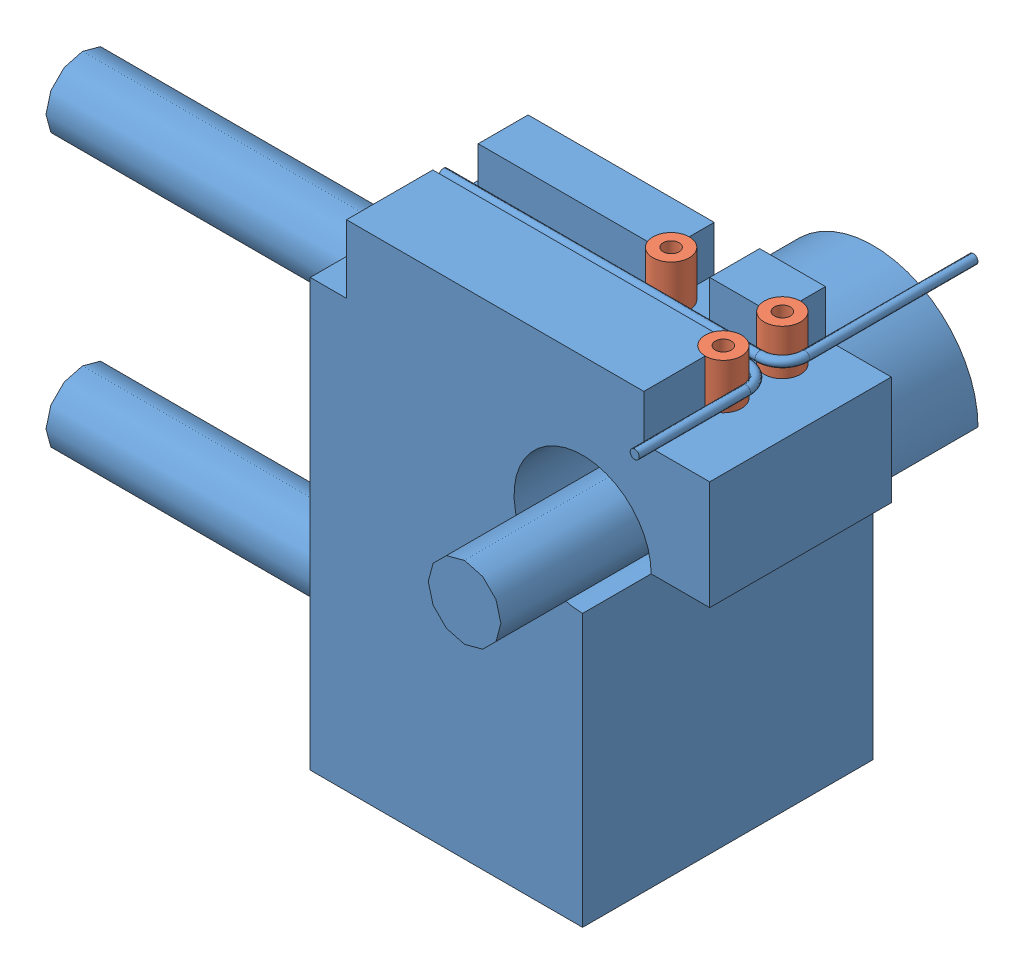
SolidWorks assembly Gantry Holder, vert, assy, configuration Default. Lengths in mm.
Overall size (44 54.5 37.3).
8 component instances, 3 part files, 24 mates.
Components (placement in the parent):
- Gantry Holder, Vert Rod-1: Gantry Holder, Vert Rod [Default] at origin size (81.1 54.5 50)
- 12 x 4 x 4 bearing-1: 12 x 4 x 4 bearing [Default] at (6.75 18 -3.25) size (12 4 12) (hidden)
- 12 x 4 x 4 bearing-2: 12 x 4 x 4 bearing [Default] at (6.75 22 -3.25) size (12 4 12) (hidden)
- 12 x 4 x 4 bearing-3: 12 x 4 x 4 bearing [Default] at (6.75 22 3.25) x (0.997259 0 -0.073987) z (0.073987 0 0.997259) size (12 4 12) (hidden)
- 12 x 4 x 4 bearing-4: 12 x 4 x 4 bearing [Default] at (6.75 18 3.25) x (0.584981 0 -0.811047) z (0.811047 0 0.584981) size (12 4 12) (hidden)
- 4mm dowel-1: 4mm dowel [Default] at (6.75 5 3.25) x (0.933427 0 -0.358767) z (0.358767 0 0.933427) size (4 12 4)
- 4mm dowel-2: 4mm dowel [Default] at (6.75 5 -3.25) x (0.21535 0 0.976537) z (-0.976537 0 0.21535) size (4 12 4)
- 4mm dowel-3: 4mm dowel [Default] at (-5.5 5 -3.25) x (0.21535 0 0.976537) z (-0.976537 0 0.21535) size (4 12 4)
Mates (geometry in assembly coordinates):
- Coincident1: coincident anti-aligned: plane of 12 x 4 x 4 bearing-1 through (12.25 22 -3.25) normal (0 1 0); plane of 12 x 4 x 4 bearing-2 through (9.25 22 -3.25) normal (0 -1 0)
- Concentric1: concentric aligned: cylinder of 12 x 4 x 4 bearing-1 through (6.75 18 -3.25) axis (0 -1 0) radius 6; cylinder of 12 x 4 x 4 bearing-2 through (6.75 22 -3.25) axis (0 -1 0) radius 6
- Coincident2: coincident anti-aligned: plane of 12 x 4 x 4 bearing-3 through (9.2431 22 3.065) normal (0 -1 0); plane of 12 x 4 x 4 bearing-4 through (9.9674 22 -1.2108) normal (0 1 0)
- Concentric2: concentric aligned: cylinder of 12 x 4 x 4 bearing-3 through (6.75 22 3.25) axis (0 -1 0) radius 6; cylinder of 12 x 4 x 4 bearing-4 through (6.75 18 3.25) axis (0 -1 0) radius 6
- Concentric3: concentric: cylinder of assembly; point of Gantry Holder, Vert Rod-1; cylinder of 12 x 4 x 4 bearing-4 through (6.75 18 3.25) axis (0 -1 0) radius 2
- Distance1: distance = 1 mm anti-aligned: plane of Gantry Holder, Vert Rod-1 through (0 17 12) normal (0 1 0); plane of 12 x 4 x 4 bearing-4 through (8.2125 18 1.2224) normal (0 -1 0)
- Coincident5: coincident aligned: plane of 12 x 4 x 4 bearing-1 through (9.25 18 -3.25) normal (0 -1 0); plane of 12 x 4 x 4 bearing-4 through (8.2125 18 1.2224) normal (0 -1 0)
- Concentric4: concentric: cylinder of assembly; point of Gantry Holder, Vert Rod-1; cylinder of 12 x 4 x 4 bearing-1 through (6.75 18 -3.25) axis (0 -1 0) radius 2
- Concentric5: concentric: cylinder of 12 x 4 x 4 bearing-4 through (6.75 18 3.25) axis (0 -1 0) radius 2
- Coincident8: coincident: plane of 12 x 4 x 4 bearing-4 through (9.9674 22 -1.2108) normal (0 1 0)
- Parallel1: parallel aligned: plane of Gantry Holder, Vert Rod-1 through (0 0 12) normal (0 0 1); plane of string-1 through (9 17 53) normal (0 0 1)
- Concentric6: concentric: cylinder of 12 x 4 x 4 bearing-1 through (6.75 18 -3.25) axis (0 -1 0) radius 2
- Coincident11: coincident: plane of 12 x 4 x 4 bearing-1 through (12.25 22 -3.25) normal (0 1 0)
- Parallel2: parallel: plane of Gantry Holder, Vert Rod-1 through (0 17 12) normal (0 1 0); line of string-2 through (9 17 -53) axis (0 0 1)
- Parallel3: parallel: plane of Gantry Holder, Vert Rod-1 through (0 17 12) normal (0 1 0); line of string-2 through (3 17 3) axis (-1 0 0)
- Parallel4: parallel: plane of Gantry Holder, Vert Rod-1 through (0 0 12) normal (0 0 1); line of string-2 through (3 17 3) axis (-1 0 0)
- Parallel5: parallel: plane of Gantry Holder, Vert Rod-1 through (0 17 12) normal (0 1 0); line of string-1 through (-47 17 -3) axis (1 0 0)
- Coincident12: coordinate: unknown of Gantry Holder, Vert Rod-1
- Concentric7: concentric anti-aligned: cylinder of Gantry Holder, Vert Rod-1 through (6.75 17 3.25) axis (0 1 0) radius 2; cylinder of 4mm dowel-1 through (6.75 17 3.25) axis (0 -1 0) radius 2
- Concentric8: concentric anti-aligned: cylinder of Gantry Holder, Vert Rod-1 through (6.75 17 -3.25) axis (0 1 0) radius 2; cylinder of 4mm dowel-2 through (6.75 17 -3.25) axis (0 -1 0) radius 2
- Coincident13: coincident aligned: plane of 4mm dowel-1 through (6.75 17 3.25) normal (0 1 0); plane of 4mm dowel-2 through (6.75 17 -3.25) normal (0 1 0)
- Coincident14: coincident aligned: plane of Gantry Holder, Vert Rod-1 through (0 17 12) normal (0 1 0); plane of 4mm dowel-2 through (6.75 17 -3.25) normal (0 1 0)
- Concentric9: concentric anti-aligned: cylinder of Gantry Holder, Vert Rod-1 through (-5.5 17 -3.25) axis (0 1 0) radius 2; cylinder of 4mm dowel-3 through (-5.5 17 -3.25) axis (0 -1 0) radius 2
- Coincident15: coincident aligned: plane of 4mm dowel-2 through (6.75 17 -3.25) normal (0 1 0); plane of 4mm dowel-3 through (-5.5 17 -3.25) normal (0 1 0)
